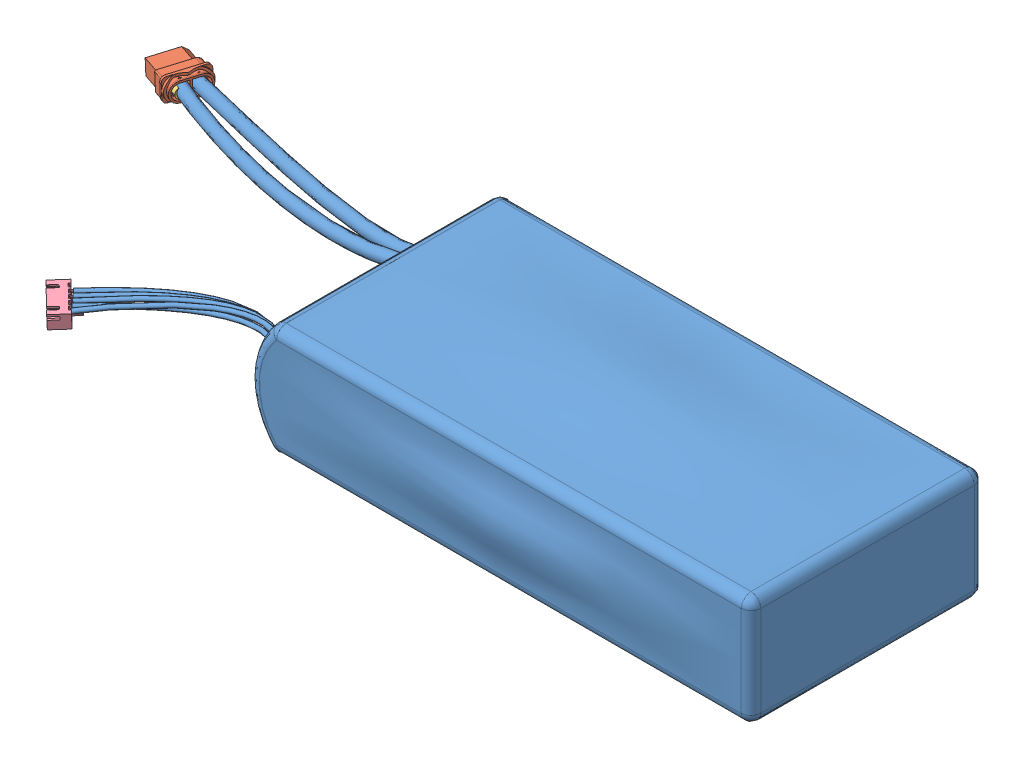
SolidWorks assembly ass1, configuration Default. Lengths in mm.
Overall size (337.4 54.47 123.76).
6 component instances, 4 part files, 1 mates.
Components (placement in the parent):
- Copy of Part214^ass1-1: Copy of Part214^ass1 [Default] at (-90.4116 41.5902 64.6831) size (323.46 54.47 113.12) (virtual)
- XT60H-F v3.step-1: XT60H-F v3.step [Default] at (-213.9308 18.4711 -25.9525) x (-0.328773 -0.031546 0.943882) z (-0.944095 -0.014804 -0.329342) size (16.55 9.35 20.75)
  - Housing.step-1: Housing.step [Default] at origin size (16.55 9.35 17)
  - Contact.step-1: Contact.step [Default] at origin size (4.27 4.27 19.35)
  - Contact.step-2: Contact.step [Default] x (-1 0 0) z (0 0 1) size (4.27 4.27 19.35)
- JST 5pin.stp-1: JST 5pin.stp [Default] at (-168.6555 15.518 68.2208) x (-0.058231 -0.992387 -0.108527) z (-0.7106 0.11756 -0.693706) size (5.91 10.59 14.91)
Mates (geometry in assembly coordinates):
- Parallel1: parallel anti-aligned: plane of Copy of Part214^ass1-1 through (-166.2969 18.5902 69.6752) normal (-0.701182 -0.036724 0.712035); plane of JST 5pin.stp-1 through (-164.2702 18.8196 67.8581) normal (0.701182 0.036724 -0.712035)
